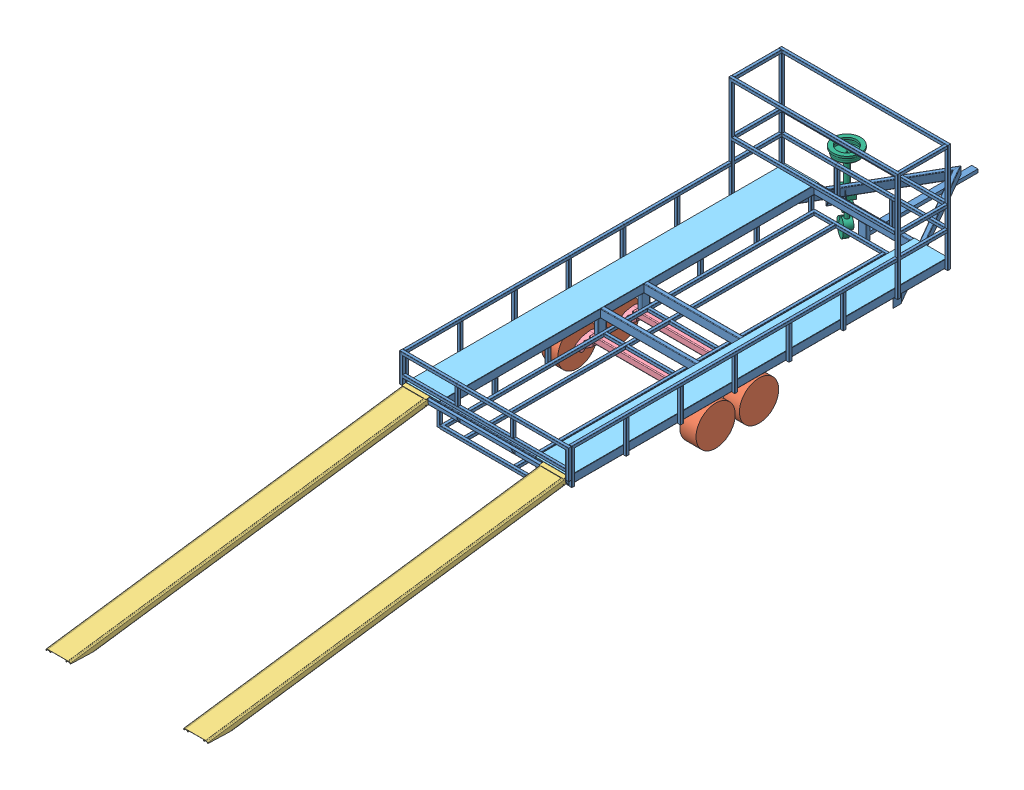
SolidWorks assembly Trailer, configuration Default. Lengths in mm.
Overall size (2023.8 1962.13 11093.66).
12 component instances, 6 part files, 32 mates.
Components (placement in the parent):
- Frame-1: Frame [Default<As Machined>] at (0 589.75 0) x (0 0 1) z (-1 0 0) size (7723.94 1497.9 2023.8)
- Tire-1: Tire [Default] at (-925 234.95 459.9) x (0 0.083962 0.996469) z (-1 0 0) size (469.9 469.9 195)
- Tire-2: Tire [Default] at (-925 234.95 -60) x (0 -0.706518 0.707695) z (-1 0 0) size (469.9 469.9 195)
- Tire-3: Tire [Default] at (730 234.95 459.9) x (0 0.617646 0.786456) z (-1 0 0) size (469.9 469.9 195)
- Tire-4: Tire [Default] at (730 234.95 -60) x (0 0 1) z (-1 0 0) size (469.9 469.9 195)
- Ramp-1: Ramp [Default<As Machined>] at (-823.6 343.5005 4433.8766) x (1 0 0) z (0 -0.137648 0.990481) size (290.8 85.2 4585.43)
- Ramp-2: Ramp [Default<As Machined>] at (823.6 343.5005 4433.8766) x (1 0 0) z (0 -0.137648 0.990481) size (290.8 85.2 4585.43)
- Axle-1: Axle [Default] at (0 234.95 -60) x (-1 0 0) z (0 0 -1) size (1938.93 207 325)
- Axle-2: Axle [Default] at (0 234.95 459.9) x (-1 0 0) z (0 0 -1) size (1938.93 207 325)
- Treadplate-1: Treadplate [Default] at origin size (400 2 4540)
- Treadplate-2: Treadplate [Default] at (1550 0 0) size (400 2 4540)
- FrontWheel-1: FrontWheel [Default] at (-493.6919 397.8438 -2547.4323) x (-0.5 0 0.866025) z (-0.866025 0 -0.5) size (330 1025.12 430)
Mates (geometry in assembly coordinates):
- Concentric1: concentric aligned: cylinder of Tire-2 through (-730 234.95 -60) axis (-1 0 0) radius 234.95; cylinder of Tire-4 through (925 234.95 -60) axis (-1 0 0) radius 234.95
- Concentric2: concentric aligned: cylinder of Tire-1 through (-730 234.95 459.9) axis (-1 0 0) radius 234.95; cylinder of Tire-3 through (925 234.95 459.9) axis (-1 0 0) radius 234.95
- Distance1: distance = 1850 mm anti-aligned: plane of Tire-2 through (-925 234.95 -60) normal (-1 0 0); plane of Tire-4 through (925 234.95 -60) normal (1 0 0)
- Distance2: distance = 1850 mm anti-aligned: plane of Tire-1 through (-925 234.95 459.9) normal (-1 0 0); plane of Tire-3 through (925 234.95 459.9) normal (1 0 0)
- Tangent1: tangent anti-aligned: cylinder of Tire-1 through (-730 234.95 459.9) axis (-1 0 0) radius 234.95; plane of assembly through (0 0 0) normal (0 1 0)
- Tangent2: tangent anti-aligned: cylinder of Tire-2 through (-730 234.95 -60) axis (-1 0 0) radius 234.95; plane of assembly through (0 0 0) normal (0 1 0)
- Coincident3: coincident aligned: plane of Tire-1 through (-925 234.95 459.9) normal (-1 0 0); plane of Tire-2 through (-925 234.95 -60) normal (-1 0 0)
- Coincident5: coincident anti-aligned: plane of Frame-1 through (0 589.75 0) normal (-1 0 0); plane of assembly through (0 0 0) normal (1 0 0)
- Distance4: distance = 925 mm anti-aligned: plane of Tire-1 through (-925 234.95 459.9) normal (-1 0 0); plane of assembly through (0 0 0) normal (1 0 0)
- Distance5: distance = 50 mm: cylinder of Tire-2 through (-730 234.95 -60) axis (-1 0 0) radius 234.95; cylinder of Tire-1 through (-730 234.95 459.9) axis (-1 0 0) radius 234.95
- Distance6: distance = 69.85 mm anti-aligned: cylinder of Tire-1 through (-730 234.95 459.9) axis (-1 0 0) radius 234.95; plane of Frame-1 through (-931.4 539.75 -2270) normal (0 -1 0)
- Parallel1: parallel aligned: plane of Frame-1; plane of assembly through (0 0 0) normal (0 1 0)
- Coincident16: coincident aligned: plane of Frame-1 through (0 589.75 0) normal (0 0 1); plane of assembly through (0 0 0) normal (0 0 1)
- Angle1: planar angle = 0.05236 rad aligned: plane of Ramp-1; plane of assembly through (0 0 0) normal (0 1 0)
- Coincident20: coincident aligned: line of Ramp-1 through (-943.6 42.1347 6587.8978) axis (1 0 0); line of Ramp-2 through (703.6 42.1347 6587.8978) axis (1 0 0)
- Coincident22: coincident anti-aligned: plane of Axle-1 through (0 234.95 -60) normal (-1 0 0); plane of assembly through (0 0 0) normal (1 0 0)
- Parallel2: parallel aligned: plane of Axle-1; plane of assembly through (0 0 0) normal (0 1 0)
- Concentric4: concentric anti-aligned: cylinder of Tire-2 through (-730 234.95 -60) axis (-1 0 0) radius 234.95; cylinder of Axle-1 through (-657.8962 234.95 -60) axis (1 0 0) radius 80
- Coincident24: coincident anti-aligned: plane of Axle-2 through (0 234.95 459.9) normal (-1 0 0); plane of assembly through (0 0 0) normal (1 0 0)
- Parallel3: parallel aligned: plane of Axle-2; plane of assembly through (0 0 0) normal (0 1 0)
- Concentric5: concentric anti-aligned: cylinder of Tire-1 through (-730 234.95 459.9) axis (-1 0 0) radius 234.95; cylinder of Axle-2 through (-657.8962 234.95 459.9) axis (1 0 0) radius 80
- Distance11: distance = 260 mm: line of Axle-1 through (-969.4625 234.95 -60) axis (1 0 0); plane of Frame-1 through (0 589.75 200) normal (0 0 1)
- Coincident25: coincident anti-aligned: plane of Frame-1 through (975 639.75 -2263.6) normal (0 1 0); plane of Treadplate-2 through (1550 639.75 0) normal (0 -1 0)
- Coincident26: coincident aligned: plane of Treadplate-1 through (-975 641.75 -2270) normal (0 0 -1); plane of Treadplate-2 through (575 641.75 -2270) normal (0 0 -1)
- Coincident27: coincident aligned: plane of Frame-1 through (975 633.35 2270) normal (1 0 0); plane of Treadplate-2 through (975 641.75 -2270) normal (1 0 0)
- Parallel4: parallel aligned: plane of FrontWheel-1; plane of assembly through (0 0 0) normal (0 1 0)
- Coincident31: coincident anti-aligned: plane of Frame-1 through (-946.6506 446.15 -1762.8848) normal (-0.866025 0 -0.5); plane of FrontWheel-1 through (-493.6919 397.8438 -2547.4323) normal (0.866025 0 0.5)
- Tangent4: tangent anti-aligned: cylinder of Frame-1 through (945 623.75 2290.5) axis (-1 0 0) radius 13.45; plane of Ramp-1 through (-1038.2965 595.3422 2272.9729) normal (0 -0.137648 0.990481)
- Coincident32: coincident aligned: plane of Ramp-1 through (-823.6 343.5005 4433.8766) normal (0 0.990481 0.137648); plane of Ramp-2 through (823.6 343.5005 4433.8766) normal (0 0.990481 0.137648)
- Coincident33: coincident anti-aligned: plane of Frame-1 through (-969 601.25 2276.5) normal (1 0 0); plane of Ramp-1 through (-969 -20.7609 6579.1572) normal (-1 0 0)
- Coincident34: coincident anti-aligned: plane of Frame-1 through (969 601.25 2276.5) normal (-1 0 0); plane of Ramp-2 through (969 29.5556 6586.1497) normal (1 0 0)
- Tangent5: tangent anti-aligned: cylinder of Frame-1 through (945 623.75 2290.5) axis (-1 0 0) radius 13.45; plane of Ramp-1 through (-969 637.0651 2292.4009) normal (0 -0.990481 -0.137648)
